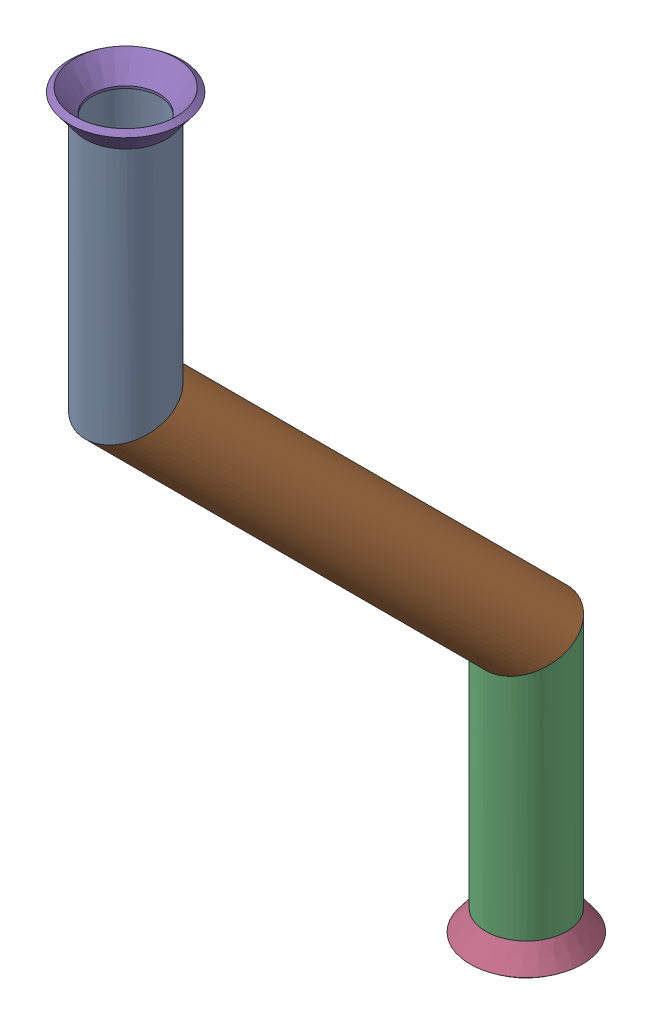
SolidWorks assembly Pipe 4, configuration Default. Lengths in mm.
Overall size (17.59 146.84 80.46).
3 component instances, 2 part files, 4 mates.
Components (placement in the parent):
- Part2-1: Part2 [Default<As Machined>] at origin size (12.7 139.06 75.56)
- Flared pipe end - .5 inch-1: Flared pipe end - .5 inch [Default<As Machined>] at (0 -189.578 244.7365) x (1 0 -0.00017) z (0 -1 0) size (17.59 17.59 3.89)
- Flared pipe end - .5 inch-2: Flared pipe end - .5 inch [Default<As Machined>] at (0 -50.5162 307.5983) x (1 0 0.00017) z (0 1 0) size (17.59 17.59 3.89)
Mates (geometry in assembly coordinates):
- Coincident1029: coincident: plane of Part2-1 through (0 -189.578 244.7365) normal (0 -1 0); plane of Flared pipe end - .5 inch-1 through (0.0009 -189.578 250.0197) normal (0 1 0)
- Concentric657: concentric: circle of Part2-1; circle of Flared pipe end - .5 inch-1
- Coincident1027: coincident: plane of Part2-1 through (0 -50.5162 307.5983) normal (0 1 0); plane of Flared pipe end - .5 inch-2 through (0.0009 -50.5162 302.3151) normal (0 -1 0)
- Concentric656: concentric: circle of Part2-1; circle of Flared pipe end - .5 inch-2
